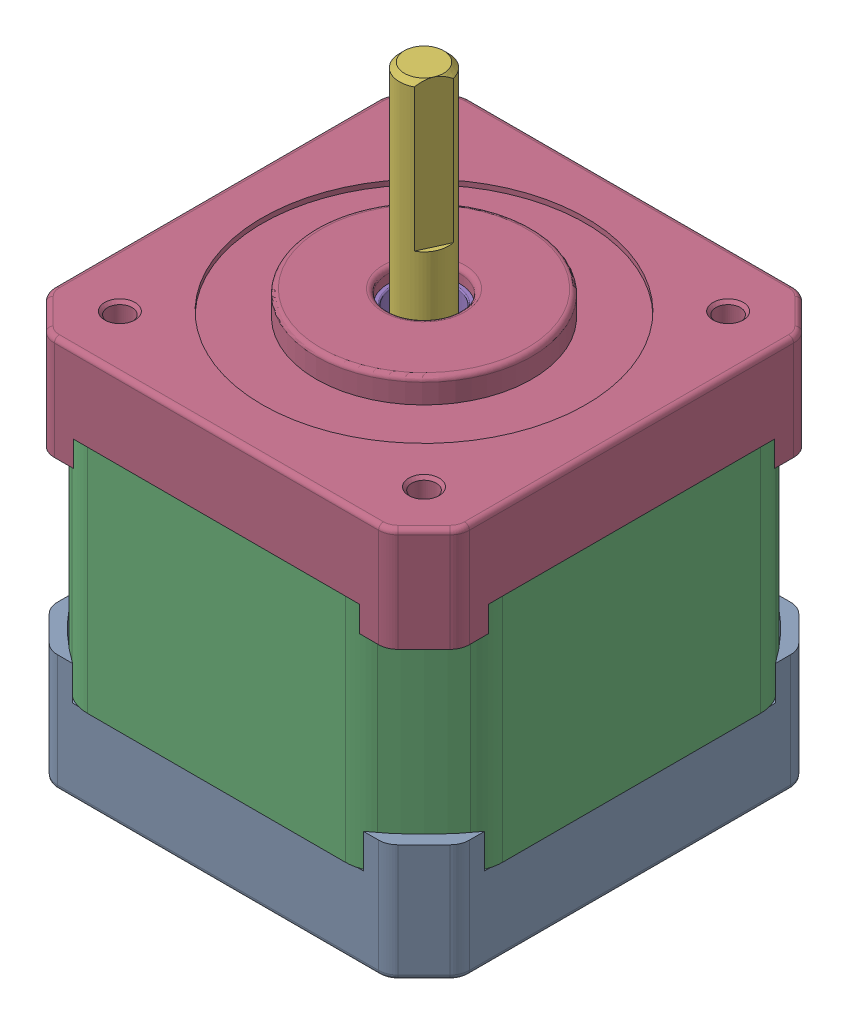
SolidWorks assembly 17HM15-0904S, configuration По умолчанию. Lengths in mm.
Overall size (42.3 62 42.3).
6 component instances, 5 part files, 16 mates.
Components (placement in the parent):
- nema17_bottom_40mm-1: nema17_bottom_40mm [По умолчанию] at origin size (42 12 42)
- radial ball bearing_68_din-1: radial ball bearing_68_din [PreviewCfg] at (0 4.0875 0) x (0 -1 0) z (0 0 1) size (3.17 12.7 12.7)
- nema17_middle_40mm-1: nema17_middle_40mm [По умолчанию] at (0 8.5 0) size (42.3 23.5 42.3)
- nema17_top_40mm-1: nema17_top_40mm [По умолчанию] at (0 32 0) size (42.3 12.6 42.3)
- radial ball bearing_68_din-3: radial ball bearing_68_din [PreviewCfg] at (0 39.0125 0) x (0 1 0) z (0 0 1) size (3.17 12.7 12.7)
- nema17_shaft_40mm-1: nema17_shaft_40mm [По умолчанию] at (0 2 0) x (-0.412738 0 0.91085) z (-0.91085 0 -0.412738) size (5 60 5)
Mates (geometry in assembly coordinates):
- Совпадение1: coincident anti-aligned: plane of nema17_bottom_40mm-1 through (0 2.5 0) normal (0 1 0); plane of radial ball bearing_68_din-1 through (6.223 2.5 0) normal (0 -1 0)
- Концентричный1: concentric anti-aligned: cylinder of nema17_bottom_40mm-1 through (0 2.5 0) axis (0 1 0) radius 8; cylinder of radial ball bearing_68_din-1 through (0 24.725 0) axis (0 -1 0) radius 6.35
- Концентричный2: concentric aligned: cylinder of nema17_bottom_40mm-1 through (15.5 8.5 15.5) axis (0 -1 0) radius 1.25; cylinder of nema17_middle_40mm-1 through (15.5 32 15.5) axis (0 -1 0) radius 1.25
- Концентричный3: concentric aligned: cylinder of nema17_bottom_40mm-1 through (-15.5 8.5 -15.5) axis (0 -1 0) radius 1.25; cylinder of nema17_middle_40mm-1 through (-15.5 32 -15.5) axis (0 -1 0) radius 1.25
- Совпадение2: coincident anti-aligned: plane of nema17_bottom_40mm-1 through (0 8.5 0) normal (0 1 0); plane of nema17_middle_40mm-1 through (0 8.5 0) normal (0 -1 0)
- Концентричный4: concentric aligned: cylinder of nema17_middle_40mm-1 through (15.5 32 15.5) axis (0 -1 0) radius 1.25; cylinder of nema17_top_40mm-1 through (15.5 40 15.5) axis (0 -1 0) radius 1.25
- Концентричный5: concentric aligned: cylinder of nema17_middle_40mm-1 through (-15.5 32 -15.5) axis (0 -1 0) radius 1.25; cylinder of nema17_top_40mm-1 through (-15.5 40 -15.5) axis (0 -1 0) radius 1.25
- Совпадение3: coincident anti-aligned: plane of nema17_middle_40mm-1 through (0 32 0) normal (0 1 0); plane of nema17_top_40mm-1 through (0 32 0) normal (0 -1 0)
- Совпадение4: coincident anti-aligned: plane of nema17_top_40mm-1 through (0 40.6 0) normal (0 -1 0); plane of radial ball bearing_68_din-3 through (-6.223 40.6 0) normal (0 1 0)
- Концентричный6: concentric anti-aligned: cylinder of nema17_top_40mm-1 through (0 40.6 0) axis (0 -1 0) radius 8; cylinder of radial ball bearing_68_din-3 through (0 18.375 0) axis (0 1 0) radius 6.35
- Совпадение5: coincident aligned: cone of nema17_bottom_40mm-1 through (15.5 0 15.5) axis (0 1 0); cone of countersunk flat head cross recess screw_din-1 through (15.5 1.5924 15.5) axis (0 1 0)
- Совпадение6: coincident aligned: cone of nema17_bottom_40mm-1 through (15.5 0 -15.5) axis (0 1 0); cone of countersunk flat head cross recess screw_din-2 through (15.5 1.5924 -15.5) axis (0 1 0)
- Совпадение7: coincident aligned: cone of nema17_bottom_40mm-1 through (-15.5 0 15.5) axis (0 1 0); cone of countersunk flat head cross recess screw_din-3 through (-15.5 1.5924 15.5) axis (0 1 0)
- Совпадение8: coincident aligned: cone of nema17_bottom_40mm-1 through (-15.5 0 -15.5) axis (0 1 0); cone of countersunk flat head cross recess screw_din-4 through (-15.5 1.5924 -15.5) axis (0 1 0)
- Концентричный8: concentric aligned: cylinder of nema17_top_40mm-1 through (0 42 0) axis (0 -1 0) radius 3.65; cylinder of nema17_shaft_40mm-1 through (0 62 0) axis (0 -1 0) radius 2.5
- Расстояние1: distance = 22 mm aligned: plane of nema17_shaft_40mm-1 through (0 62 0) normal (0 1 0); plane of nema17_top_40mm-1 through (0 40 0) normal (0 1 0)
